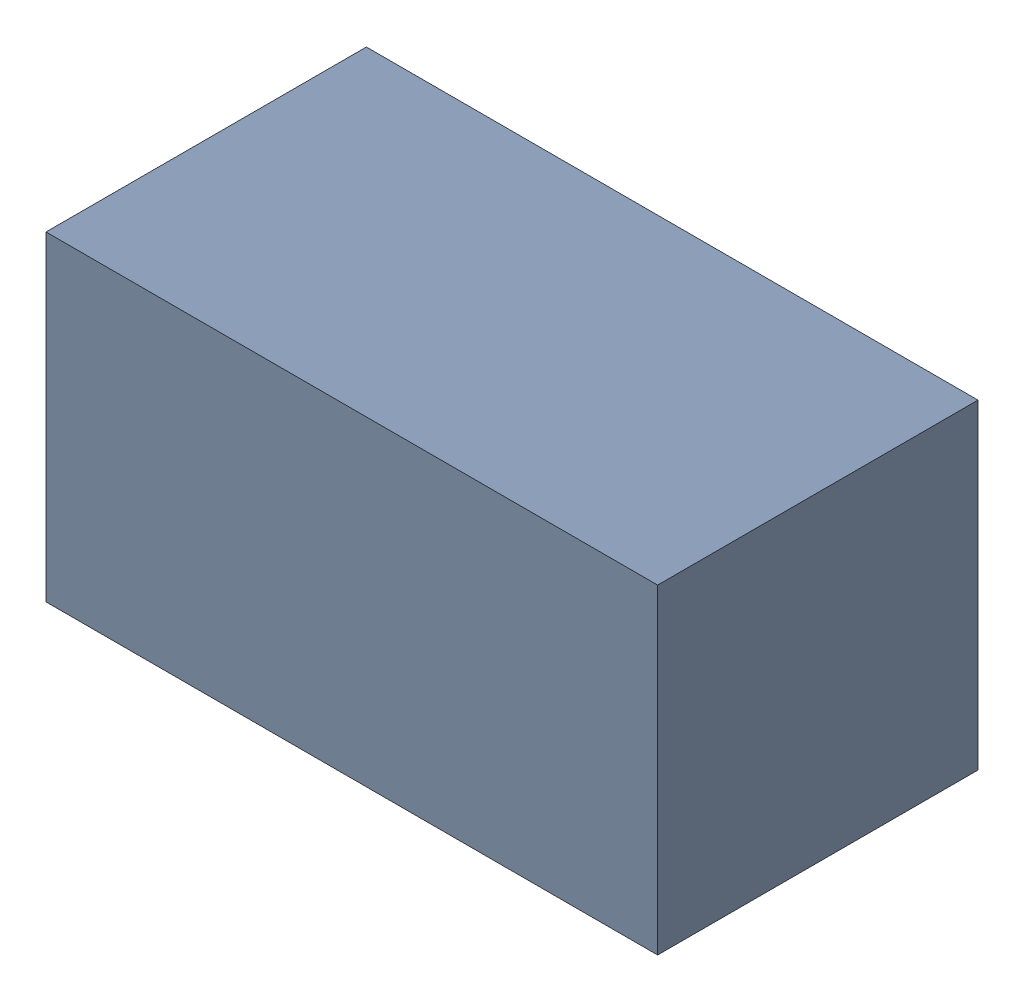
SolidWorks assembly 6327398848, configuration Default. Lengths in mm.
Overall size (0.63 0.33 0.33).
2 component instances, 1 part files, 0 mates.
Components (placement in the parent):
- 6701982208-1:  [Default] at (27.7 14.8 0) (suppressed, hidden)
- Extruded-20-1: Extruded-20 [Default] at origin size (0.63 0.33 0.33)
